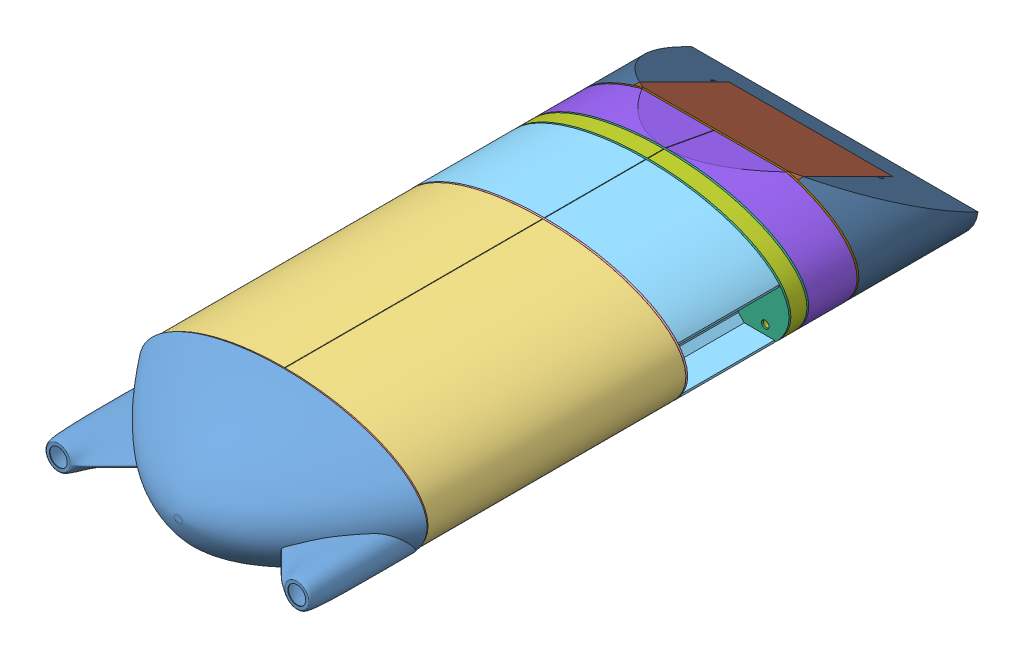
SolidWorks assembly fuselageAssem_v1c, configuration Default. Lengths in mm.
Overall size (564.88 295.36 1102.55).
13 component instances, 12 part files, 47 mates.
Components (placement in the parent):
- fuselageNose_v1.3-1: fuselageNose_v1.3 [Default] at (0 0 3) size (564.88 295.36 183.96)
- fuselagePlate_v1.1-1: fuselagePlate_v1.1 [Default] at origin size (488 220 3)
- fuselageBodyS1_v1.3-1: fuselageBodyS1_v1.3 [52_4] at origin size (488 220 432.44)
- fuselagePlatePaxCargoFore_v1.1-1: fuselagePlatePaxCargoFore_v1.1 [52_4] at (0 0 -432.44) size (488 220 3)
- fuselageBodyConnector_v1.2-1: fuselageBodyConnector_v1.2 [52_4] at (0 0 -435.44) size (454.98 220 170)
- fuselagePlatePaxCargoAft_v1.1-3: fuselagePlatePaxCargoAft_v1.1 [52_4] at (0 0 -605.44) size (488 220 3)
- fuselageBodyS2_v1.2-1: fuselageBodyS2_v1.2 [52_4] at (0 0 -608.44) size (488 220 27.03)
- fuselagePlatePaxCargoAft_v1.1-4: fuselagePlatePaxCargoAft_v1.1 [52_4] at (0 0 -635.4675) size (488 220 3)
- fuselageBodyS3_v1.3-1: fuselageBodyS3_v1.3 [52_4] at (0 0 -638.4675) size (488 220 81.08)
- fuselagePlateEnd_v1.2-1: fuselagePlateEnd_v1.2 [52_4] at (0 0 -719.55) size (488 200 3)
- fuselageBodyS4_v1.2-1: fuselageBodyS4_v1.2 [52_4] at (0 0 -722.55) size (488 204.92 200)
- fuselageBodyS4InsertUpper_v1.2-2: fuselageBodyS4InsertUpper_v1.2 [52_4] at (0 0 -722.55) size (275 79.9 159.8)
- fuselageBodyS4InsertLower_v1.2-1: fuselageBodyS4InsertLower_v1.2 [52_4] at (0 0 -722.55) size (152.4 90 200)
Mates (geometry in assembly coordinates):
- Coincident1: coincident aligned: plane of fuselageBodyS1_v1.3-1 through (0 0 0) normal (0 0 1); plane of assembly through (0 0 0) normal (0 0 1)
- Coincident2: coincident aligned: plane of fuselageBodyS1_v1.3-1 through (0 0 0) normal (0 1 0); plane of assembly through (0 0 0) normal (0 1 0)
- Coincident3: coincident aligned: plane of fuselageBodyS1_v1.3-1 through (0 0 0) normal (1 0 0); plane of assembly through (0 0 0) normal (1 0 0)
- Coincident5: coincident aligned: plane of fuselageBodyS3_v1.3-1 through (0 0 -638.4675) normal (1 0 0); plane of assembly through (0 0 0) normal (1 0 0)
- Coincident7: coincident aligned: plane of fuselageBodyConnector_v1.2-1 through (0 0 -435.44) normal (0 1 0); plane of assembly through (0 0 0) normal (0 1 0)
- Coincident8: coincident aligned: plane of fuselageBodyConnector_v1.2-1 through (0 0 -435.44) normal (1 0 0); plane of assembly through (0 0 0) normal (1 0 0)
- Coincident10: coincident aligned: plane of fuselageBodyS2_v1.2-1 through (0 0 -608.44) normal (0 1 0); plane of assembly through (0 0 0) normal (0 1 0)
- Coincident11: coincident aligned: plane of fuselageBodyS2_v1.2-1 through (0 0 -608.44) normal (1 0 0); plane of assembly through (0 0 0) normal (1 0 0)
- Coincident13: coincident aligned: plane of fuselageBodyS3_v1.3-1 through (0 0 -638.4675) normal (0 1 0); plane of assembly through (0 0 0) normal (0 1 0)
- Coincident15: coincident aligned: plane of fuselageBodyS4_v1.2-1 through (0 0 -722.55) normal (0 1 0); plane of assembly through (0 0 0) normal (0 1 0)
- Coincident16: coincident aligned: plane of fuselageBodyS4_v1.2-1 through (0 0 -722.55) normal (1 0 0); plane of assembly through (0 0 0) normal (1 0 0)
- Coincident18: coincident aligned: plane of ? through (0 0 -22) normal (0 1 0); plane of assembly through (0 0 0) normal (0 1 0)
- Coincident19: coincident aligned: plane of ? through (0 0 -22) normal (1 0 0); plane of assembly through (0 0 0) normal (1 0 0)
- Coincident20: coincident anti-aligned: plane of fuselageBodyS1_v1.3-1 through (0 0 0) normal (0 0 1); plane of fuselagePlate_v1.1-1 through (0 0 0) normal (0 0 -1)
- Coincident21: coincident aligned: plane of fuselagePlate_v1.1-1 through (0 0 0) normal (0 1 0); plane of assembly through (0 0 0) normal (0 1 0)
- Coincident22: coincident aligned: plane of fuselagePlate_v1.1-1 through (0 0 0) normal (1 0 0); plane of assembly through (0 0 0) normal (1 0 0)
- Coincident27: coincident aligned: plane of fuselagePlatePaxCargoAft_v1.1-3 through (0 0 -605.44) normal (0 1 0); plane of assembly through (0 0 0) normal (0 1 0)
- Coincident28: coincident aligned: plane of fuselagePlatePaxCargoAft_v1.1-3 through (0 0 -605.44) normal (1 0 0); plane of assembly through (0 0 0) normal (1 0 0)
- Coincident29: coincident anti-aligned: plane of fuselageBodyConnector_v1.2-1 through (0 0 -605.44) normal (0 0 -1); plane of fuselagePlatePaxCargoAft_v1.1-3 through (0 0 -605.44) normal (0 0 1)
- Coincident30: coincident anti-aligned: plane of fuselagePlatePaxCargoAft_v1.1-3 through (0 0 -608.44) normal (0 0 -1); plane of fuselageBodyS2_v1.2-1 through (0 0 -608.44) normal (0 0 1)
- Coincident32: coincident aligned: plane of fuselagePlatePaxCargoAft_v1.1-4 through (0 0 -635.4675) normal (1 0 0); plane of assembly through (0 0 0) normal (1 0 0)
- Coincident33: coincident aligned: plane of fuselagePlatePaxCargoAft_v1.1-4 through (0 0 -635.4675) normal (0 1 0); plane of assembly through (0 0 0) normal (0 1 0)
- Coincident35: coincident anti-aligned: plane of fuselageBodyS3_v1.3-1 through (0 0 -719.55) normal (0 0 -1); plane of fuselagePlateEnd_v1.2-1 through (0 0 -719.55) normal (0 0 1)
- Coincident36: coincident aligned: plane of fuselagePlateEnd_v1.2-1 through (0 0 -719.55) normal (0 1 0); plane of assembly through (0 0 0) normal (0 1 0)
- Coincident37: coincident aligned: plane of fuselagePlateEnd_v1.2-1 through (0 0 -719.55) normal (1 0 0); plane of assembly through (0 0 0) normal (1 0 0)
- Coincident38: coincident anti-aligned: plane of fuselagePlateEnd_v1.2-1 through (0 0 -722.55) normal (0 0 -1); plane of fuselageBodyS4_v1.2-1 through (0 0 -722.55) normal (0 0 1)
- Coincident39: coincident aligned: plane of ? through (0 0 3) normal (0 0 1); plane of fuselagePlate_v1.1-1 through (0 0 3) normal (0 0 1)
- Coincident40: coincident aligned: plane of ? through (0 0 3) normal (0 0 1); plane of fuselagePlate_v1.1-1 through (0 0 3) normal (0 0 1)
- Coincident41: coincident aligned: plane of ? through (0 0 -22) normal (0 1 0); plane of assembly through (0 0 0) normal (0 1 0)
- Coincident42: coincident aligned: plane of ? through (0 0 -22) normal (1 0 0); plane of assembly through (0 0 0) normal (1 0 0)
- Coincident43: coincident anti-aligned: plane of fuselageBodyS2_v1.2-1 through (0 0 -635.4675) normal (0 0 -1); plane of fuselagePlatePaxCargoAft_v1.1-4 through (0 0 -635.4675) normal (0 0 1)
- Coincident44: coincident anti-aligned: plane of fuselagePlatePaxCargoAft_v1.1-4 through (0 0 -638.4675) normal (0 0 -1); plane of fuselageBodyS3_v1.3-1 through (0 0 -638.4675) normal (0 0 1)
- Coincident45: coincident aligned: plane of fuselagePlatePaxCargoAft_v1.1-4 through (0 0 -635.4675) normal (0 1 0); plane of assembly through (0 0 0) normal (0 1 0)
- Coincident46: coincident aligned: plane of fuselagePlatePaxCargoAft_v1.1-4 through (0 0 -635.4675) normal (1 0 0); plane of assembly through (0 0 0) normal (1 0 0)
- Coincident48: coincident anti-aligned: plane of fuselagePlateEnd_v1.2-1 through (0 0 -722.55) normal (0 0 -1); plane of fuselageBodyS4InsertUpper_v1.2-2 through (0 0 -722.55) normal (0 0 1)
- Coincident49: coincident aligned: plane of fuselageBodyS4InsertUpper_v1.2-2 through (0 0 -722.55) normal (1 0 0); plane of assembly through (0 0 0) normal (1 0 0)
- Coincident50: coincident anti-aligned: plane of fuselageBodyS4_v1.2-1 through (-76.2 -15 -922.55) normal (0 -1 0); plane of fuselageBodyS4InsertLower_v1.2-1 through (-76.2 -15 -922.55) normal (0 1 0)
- Coincident51: coincident anti-aligned: plane of fuselagePlateEnd_v1.2-1 through (0 0 -722.55) normal (0 0 -1); plane of fuselageBodyS4InsertLower_v1.2-1 through (0 0 -722.55) normal (0 0 1)
- Coincident52: coincident aligned: plane of fuselageBodyS4InsertLower_v1.2-1 through (0 0 -722.55) normal (1 0 0); plane of assembly through (0 0 0) normal (1 0 0)
- Coincident53: coincident anti-aligned: plane of fuselageBodyS1_v1.3-1 through (0 0 -432.44) normal (0 0 -1); plane of fuselagePlatePaxCargoFore_v1.1-1 through (0 0 -432.44) normal (0 0 1)
- Coincident54: coincident anti-aligned: plane of fuselageBodyConnector_v1.2-1 through (0 0 -435.44) normal (0 0 1); plane of fuselagePlatePaxCargoFore_v1.1-1 through (0 0 -435.44) normal (0 0 -1)
- Coincident55: coincident aligned: plane of fuselagePlatePaxCargoFore_v1.1-1 through (0 0 -432.44) normal (0 1 0); plane of assembly through (0 0 0) normal (0 1 0)
- Coincident56: coincident aligned: plane of fuselagePlatePaxCargoFore_v1.1-1 through (0 0 -432.44) normal (1 0 0); plane of assembly through (0 0 0) normal (1 0 0)
- Coincident57: coincident aligned: plane of fuselageNose_v1.3-1 through (0 0 3) normal (0 0 1); plane of fuselagePlate_v1.1-1 through (0 0 3) normal (0 0 1)
- Coincident58: coincident aligned: plane of fuselageNose_v1.3-1 through (0 0 3) normal (0 1 0); plane of assembly through (0 0 0) normal (0 1 0)
- Coincident59: coincident aligned: plane of fuselageNose_v1.3-1 through (0 0 3) normal (1 0 0); plane of assembly through (0 0 0) normal (1 0 0)
- Coincident60: coincident anti-aligned: plane of fuselageBodyS4_v1.2-1 through (137.5 15.1 -922.55) normal (0 1 0); plane of fuselageBodyS4InsertUpper_v1.2-2 through (137.5 15.1 -922.55) normal (0 -1 0)
